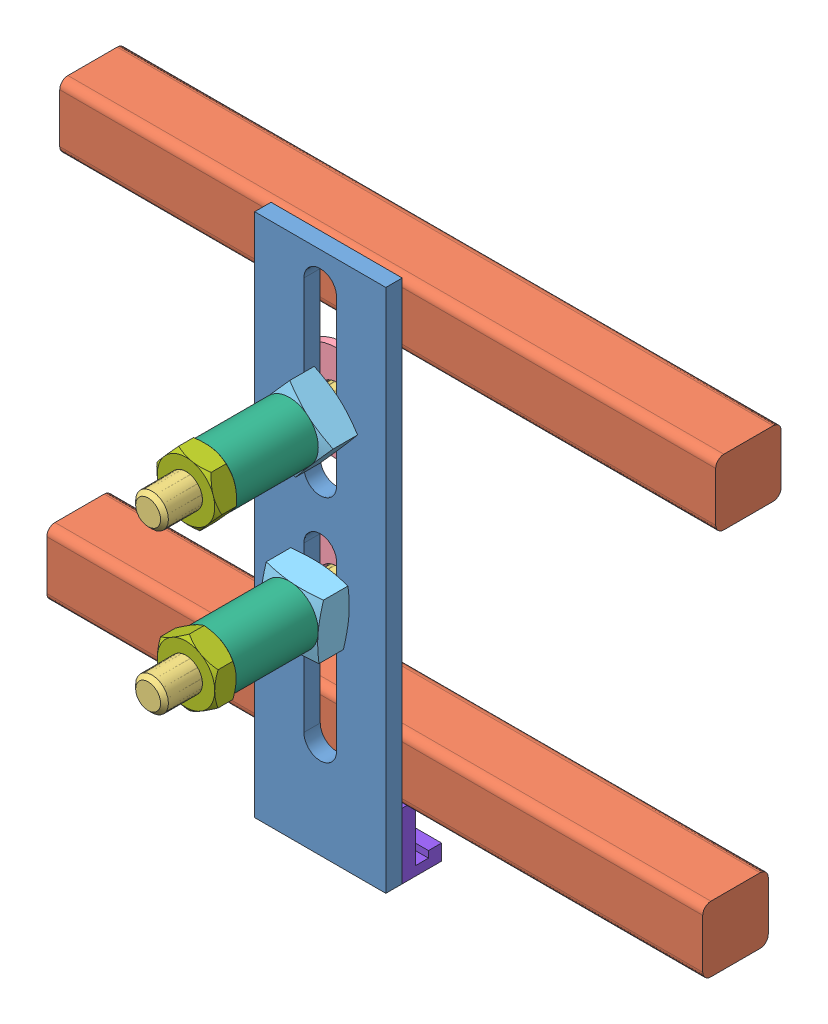
SolidWorks assembly TensionerAssembly, configuration Default. Lengths in mm.
Overall size (129.51 101.6 49.2).
14 component instances, 8 part files, 27 mates.
Components (placement in the parent):
- Back plate-1: Back plate [Default] at (28.4844 72.3492 53.0839) size (25.4 101.6 3.17)
- Bar-1: Bar [Default] at (-25.1322 85.0492 40.3839) size (127 12.7 12.7)
- Bar-2: Bar [Default] at (-27.6401 8.8492 40.3839) size (127 12.7 12.7)
- hex finished bolt_ai-1: hex finished bolt_ai [HFBOLT 0.25-20x1.5x1.5-C] at (28.4844 57.6592 47.3435) x (0 0 1) z (0 -1 0) size (42.24 12.85 11.13)
- hex finished bolt_ai-2: hex finished bolt_ai [HFBOLT 0.25-20x1.5x1.5-C] at (28.4844 26.8338 47.3435) x (0 0 1) z (1 0 0) size (42.24 12.85 11.13)
- flat washer type b regular_ai-1: flat washer type b regular_ai [Regular FW 0.25] at (28.4844 57.6592 51.4837) x (0 0 -1) z (0.867226 0.497915 0) size (1.6 18.64 18.64)
- flat washer type b regular_ai-2: flat washer type b regular_ai [Regular FW 0.25] at (28.4844 26.8338 51.4837) x (0 0 -1) z (-0.923728 -0.383049 0) size (1.6 18.64 18.64)
- square nut_61_ai-1: square nut_61_ai [SQNUT 0.2500-20-D-N] at (28.4844 57.6592 62.2279) x (0.997583 0.069483 0) z (0 0 1) size (15.73 15.73 5.97)
- square nut_61_ai-2: square nut_61_ai [SQNUT 0.2500-20-D-N] at (28.4844 26.8338 62.2279) x (0.760735 0.649062 0) z (0 0 1) size (15.73 15.73 5.97)
- Roller-1: Roller [Default] at (28.4844 57.6592 78.1029) x (0.927576 -0.373633 0) z (0.373633 0.927576 0) size (11.18 15.88 11.18)
- Roller-2: Roller [Default] at (28.4844 26.8338 62.2279) x (0.886658 0.462426 0) z (0.462426 -0.886658 0) size (11.18 15.88 11.18)
- hex jam nut_ai-2: hex jam nut_ai [HJNUT 0.2500-20-D-C] at (28.4844 57.6592 82.2431) x (0.947093 0.32096 0) z (0 0 1) size (11.11 12.83 4.14)
- hex jam nut_ai-3: hex jam nut_ai [HJNUT 0.2500-20-D-C] at (28.4844 26.8338 82.2431) size (11.11 12.83 4.14)
- Sensor Mount-1: Sensor Mount [Default] at (25.3094 -10.2008 50.5439) x (1 0 0) z (0 1 0) size (25.4 7.62 12.7)
Mates (geometry in assembly coordinates):
- Coincident13: coincident aligned: plane of Back plate-1 through (15.7844 85.0492 56.2589) normal (0 1 0); plane of Bar-1 through (101.8678 85.0492 40.3839) normal (0 1 0)
- Coincident14: coincident anti-aligned: plane of Back plate-1 through (28.4844 72.3492 53.0839) normal (0 0 -1); plane of Bar-1 through (101.8678 85.0492 53.0839) normal (0 0 1)
- Coincident16: coincident anti-aligned: plane of Back plate-1 through (28.4844 72.3492 53.0839) normal (0 0 -1); plane of Bar-2 through (99.3599 8.8492 53.0839) normal (0 0 1)
- Coincident17: coincident anti-aligned: plane of Back plate-1 through (28.4844 72.3492 53.0839) normal (1 0 0); plane of hex finished bolt_ai-1
- Concentric1: concentric anti-aligned: cylinder of hex finished bolt_ai-1 through (28.4844 57.6592 47.3435) axis (0 0 -1) radius 3.175; cylinder of flat washer type b regular_ai-1 through (28.4844 57.6592 86.4087) axis (0 0 1) radius 3.5687
- Coincident19: coincident anti-aligned: plane of hex finished bolt_ai-1 through (22.0613 57.6592 51.4837) normal (0 0 1); plane of flat washer type b regular_ai-1 through (26.7075 60.7541 51.4837) normal (0 0 -1)
- Coincident20: coincident anti-aligned: plane of Back plate-1 through (28.4844 72.3492 53.0839) normal (0 0 -1); plane of flat washer type b regular_ai-1 through (23.8429 65.7434 53.0839) normal (0 0 1)
- Concentric2: concentric anti-aligned: cylinder of hex finished bolt_ai-2 through (28.4844 26.8338 47.3435) axis (0 0 -1) radius 3.175; cylinder of flat washer type b regular_ai-2 through (28.4844 26.8338 86.4087) axis (0 0 1) radius 3.5687
- Coincident21: coincident anti-aligned: plane of hex finished bolt_ai-2 through (28.4844 20.4107 51.4837) normal (0 0 1); plane of flat washer type b regular_ai-2 through (29.8514 23.5373 51.4837) normal (0 0 -1)
- Coincident22: coincident aligned: plane of Back plate-1 through (28.4844 72.3492 53.0839) normal (1 0 0); plane of hex finished bolt_ai-2 through (28.4844 26.8338 47.3435) normal (1 0 0)
- Coincident23: coincident anti-aligned: plane of Back plate-1 through (28.4844 72.3492 53.0839) normal (0 0 -1); plane of flat washer type b regular_ai-2 through (32.0551 18.223 53.0839) normal (0 0 1)
- Concentric3: concentric anti-aligned: cylinder of hex finished bolt_ai-1 through (28.4844 57.6592 47.3435) axis (0 0 -1) radius 3.175; cylinder of square nut_61_ai-1 through (28.4844 57.6592 56.2589) axis (0 0 1) radius 2.5527
- Concentric4: concentric anti-aligned: cylinder of hex finished bolt_ai-2 through (28.4844 26.8338 47.3435) axis (0 0 -1) radius 3.175; cylinder of square nut_61_ai-2 through (28.4844 26.8338 56.2589) axis (0 0 1) radius 2.5527
- Coincident24: coincident anti-aligned: plane of Back plate-1 through (28.4844 72.3492 56.2589) normal (0 0 1); plane of square nut_61_ai-1 through (29.031 49.8116 56.2589) normal (0 0 -1)
- Coincident25: coincident anti-aligned: plane of Back plate-1 through (28.4844 72.3492 56.2589) normal (0 0 1); plane of square nut_61_ai-2 through (33.5904 20.8493 56.2589) normal (0 0 -1)
- Concentric5: concentric anti-aligned: cylinder of hex finished bolt_ai-1 through (28.4844 57.6592 47.3435) axis (0 0 -1) radius 3.175; cylinder of Roller-1 through (28.4844 57.6592 62.2279) axis (0 0 1) radius 3.9688
- Concentric6: concentric anti-aligned: cylinder of hex finished bolt_ai-2 through (28.4844 26.8338 47.3435) axis (0 0 -1) radius 3.175; circle of Roller-2
- Concentric7: concentric anti-aligned: cylinder of hex finished bolt_ai-1 through (28.4844 57.6592 47.3435) axis (0 0 -1) radius 3.175; cylinder of hex jam nut_ai-2 through (28.4844 57.6592 78.1029) axis (0 0 1) radius 2.5527
- Concentric8: concentric anti-aligned: cylinder of hex finished bolt_ai-2 through (28.4844 26.8338 47.3435) axis (0 0 -1) radius 3.175; cylinder of hex jam nut_ai-3 through (28.4844 26.8338 78.1029) axis (0 0 1) radius 2.5527
- Coincident26: coincident anti-aligned: plane of Roller-2 through (28.4844 26.8338 78.1029) normal (0 0 1); plane of hex jam nut_ai-3 through (17.3719 26.8338 78.1029) normal (0 0 -1)
- Coincident27: coincident anti-aligned: plane of square nut_61_ai-2 through (33.5904 20.8493 62.2279) normal (0 0 1); plane of Roller-2 through (28.4844 26.8338 62.2279) normal (0 0 -1)
- Coincident28: coincident anti-aligned: plane of square nut_61_ai-1 through (29.031 49.8116 62.2279) normal (0 0 1); plane of Roller-1 through (28.4844 57.6592 62.2279) normal (0 0 -1)
- Coincident29: coincident anti-aligned: plane of Roller-1 through (28.4844 57.6592 78.1029) normal (0 0 1); plane of hex jam nut_ai-2 through (17.9598 54.0926 78.1029) normal (0 0 -1)
- Distance1: distance = 12.7 mm aligned: plane of Back plate-1 through (15.7844 -16.5508 56.2589) normal (0 -1 0); plane of Bar-2 through (99.3599 -3.8508 40.3839) normal (0 -1 0)
- Coincident31: coincident anti-aligned: plane of Back plate-1 through (28.4844 72.3492 53.0839) normal (0 0 -1); plane of Sensor Mount-1 through (25.3094 -10.2008 53.0839) normal (0 0 1)
- Coincident32: coincident aligned: plane of Back plate-1 through (15.7844 -16.5508 56.2589) normal (0 -1 0); plane of Sensor Mount-1 through (25.3094 -16.5508 48.0039) normal (0 -1 0)
- Coincident33: coincident aligned: plane of Back plate-1 through (41.1844 85.0492 56.2589) normal (1 0 0); plane of Sensor Mount-1 through (41.1844 -10.2008 48.0039) normal (1 0 0)
